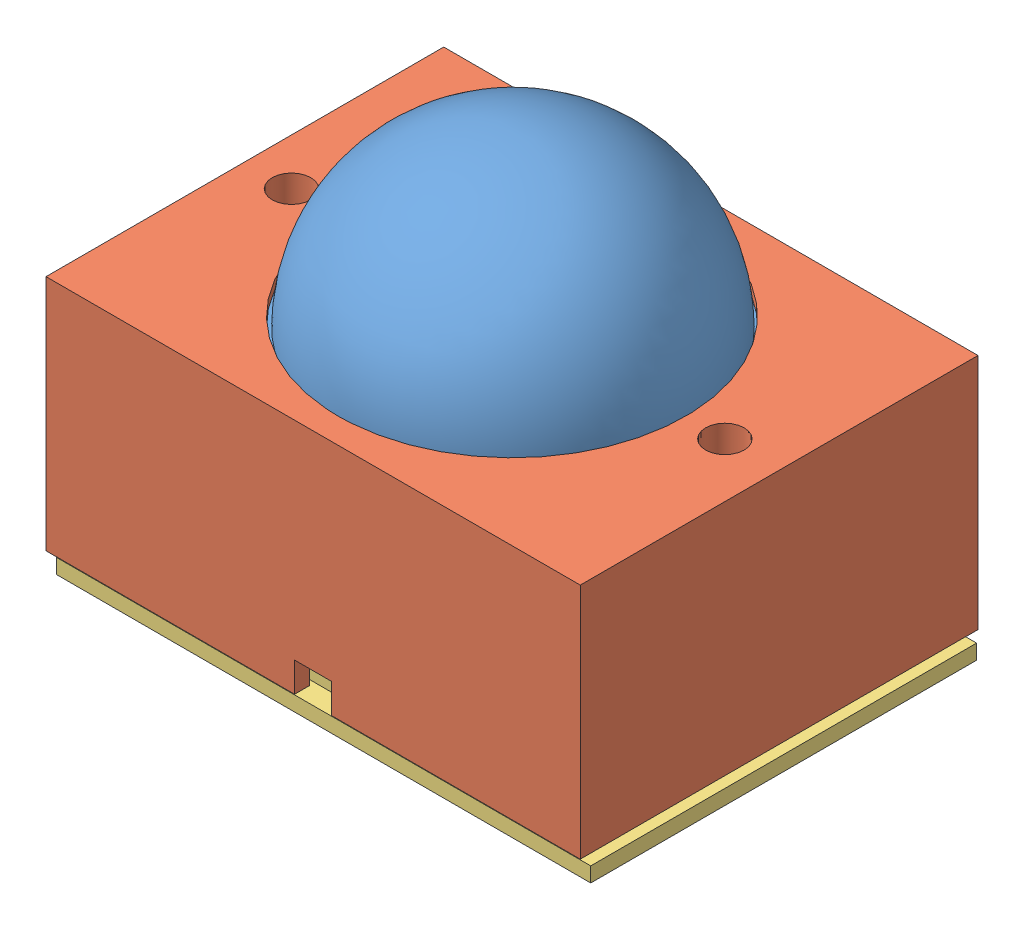
SolidWorks assembly 宿舍灯控, configuration 默认. Lengths in mm.
Overall size (170.22 59.06 61.31).
3 component instances, 3 part files, 0 mates.
Components (placement in the parent):
- 红外人体感应模块-1: 红外人体感应模块 [默认] at (151.5251 42.0424 -47.9289) size (32 26.02 24)
- 红外盒子-1: 红外盒子 [默认] at (151.4816 31.7528 -47.9099) size (36 16 26.8)
- 红外壳子底板-2: 红外壳子底板 [默认] at (152.2241 31.7583 -47.4724) size (36 2 26)
